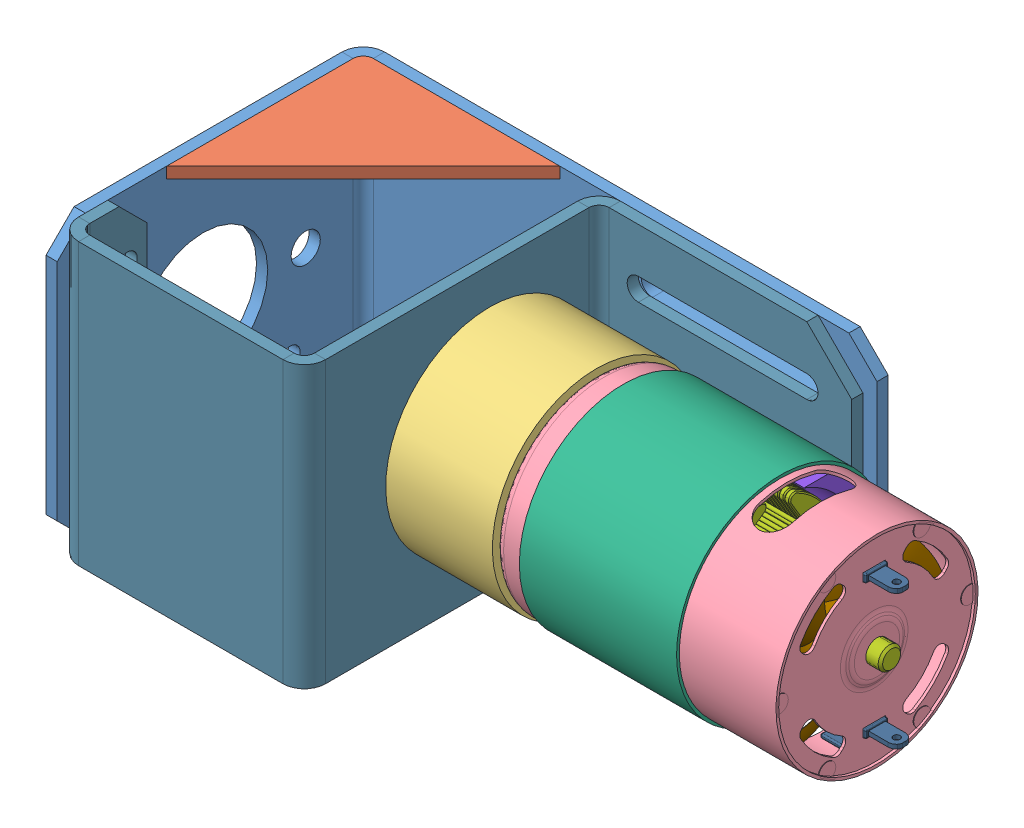
SolidWorks assembly Nema17 Holder Assem, configuration Default. Lengths in mm.
Overall size (119.88 50 56.5).
16 component instances, 14 part files, 13 mates.
Components (placement in the parent):
- Sheet Metal Nema17 LBracket-1: Sheet Metal Nema17 LBracket [Default] at (16.9581 50.3569 51.9253) size (93.5 50 56.5)
- Nema17 rib-1: Nema17 rib [Default] at (-27.7919 27.3569 53.9253) x (1 0 0) z (0 -1 0) size (35 35 2)
- Nema17 rib-2: Nema17 rib [Default] at (-27.7919 75.3569 53.9253) x (1 0 0) z (0 -1 0) size (35 35 2)
- Motor JGB37-545-1: Motor JGB37-545 [Predeterminado] at (90.0831 37.9819 73.9253) x (0 -1 0) z (-1 0 0) size (41.44 41.14 94.88)
  - Reduction box body-1: Reduction box body [Default] at (-12.375 1.5 54.875) size (37 37 25)
  - Motor body-1: Motor body [Predeterminado] at (-12.375 1.5 4.875) size (36 36 52)
  - Shaft-1: Shaft [Predeterminado] at (-12.375 8.5 67.775) x (0.863725 -0.503963 0) z (0 0 1) size (6 6 27.1)
  - Cover-1: Cover [Predeterminado] at (-12.375 1.5 22.075) size (37 36.74 28)
  - Rotor-1: Rotor [Predeterminado] at (-12.375 1.5 32.275) x (-0.951412 0.307919 0) z (0 0 1) size (26 25.6 60)
  - Magnets-1: Magnets [Default] at (-12.375 1.5 22.875) x (0 1 0) z (0 0 1) size (35 27.22 20)
  - Fan-1: Fan [Default] at (-12.375 1.5 12.975) x (-0.920955 0.389669 0) z (-0.389669 -0.920955 0) size (31.79 6.24 31.22)
  - Terminals-1: Terminals [Default] at (-12.375 1.5 5.375) x (1 0 0) z (0 0 -1) size (34 34 22.88)
  - Gear 1-1: Gear 1 [Default] at (-12.375 1.5 62.275) x (0.307919 0.951412 0) z (-0.951412 0.307919 0) size (5.97 2 5.97)
  - Gear 2-1: Gear 2 [Default] at (-12.375 -3.65 64.275) x (0.994395 0.105729 0) z (-0.105729 0.994395 0) size (20 8.6 20)
  - Gear 3-1: Gear 3 [Default] at (-12.375 8.5 66.275) x (-0.503963 -0.863725 0) z (0.863725 -0.503963 0) size (10 10 9.98)
- Part2-1: Part2 [Default] at (14.2081 50.3569 75.4253) x (0 1 0) z (1 0 0) size (50 54.5 89)
Mates (geometry in assembly coordinates):
- Coincident1: coincident anti-aligned: plane of Sheet Metal Nema17 LBracket-1 through (-27.7919 75.3569 108.4253) normal (1 0 0); plane of Nema17 rib-2 through (-27.7919 73.3569 55.7253) normal (-1 0 0)
- Coincident2: coincident anti-aligned: plane of Sheet Metal Nema17 LBracket-1 through (16.9581 50.3569 53.9253) normal (0 0 1); plane of Nema17 rib-2 through (7.2081 73.3569 53.9253) normal (0 0 -1)
- Coincident3: coincident anti-aligned: plane of Sheet Metal Nema17 LBracket-1 through (16.9581 50.3569 53.9253) normal (0 0 1); plane of Nema17 rib-1 through (7.2081 25.3569 53.9253) normal (0 0 -1)
- Coincident4: coincident anti-aligned: plane of Sheet Metal Nema17 LBracket-1 through (-27.7919 75.3569 108.4253) normal (1 0 0); plane of Nema17 rib-1 through (-27.7919 25.3569 55.7253) normal (-1 0 0)
- Coincident5: coincident aligned: plane of Sheet Metal Nema17 LBracket-1 through (-29.7919 25.3569 51.9253) normal (0 -1 0); plane of Nema17 rib-1 through (-25.9919 25.3569 55.7253) normal (0 -1 0)
- Coincident6: coincident aligned: plane of Sheet Metal Nema17 LBracket-1 through (-29.7919 75.3569 51.9253) normal (0 1 0); plane of Nema17 rib-2 through (-25.9919 75.3569 55.7253) normal (0 1 0)
- Concentric1: concentric aligned: cylinder of Sheet Metal Nema17 LBracket-1 through (-29.7919 50.3569 82.4253) axis (1 0 0) radius 11.5; cylinder of Motor JGB37-545-1/Shaft-1 through (-4.7919 50.3569 82.4253) axis (1 0 0) radius 3
- Concentric6: concentric aligned: cylinder of Motor JGB37-545-1/Shaft-1 through (-4.7919 50.3569 82.4253) axis (1 0 0) radius 3; cylinder of Part2-1 through (14.2081 50.3569 82.4253) axis (1 0 0) radius 6.5
- Coincident14: coincident aligned: plane of Sheet Metal Nema17 LBracket-1 through (-29.7919 75.3569 51.9253) normal (0 1 0); plane of Part2-1 through (16.2081 75.3569 53.9253) normal (0 1 0)
- Coincident15: coincident anti-aligned: plane of Motor JGB37-545-1/Reduction box body-1 through (16.2081 50.3569 75.4253) normal (-1 0 0); plane of Part2-1 through (16.2081 50.3569 75.4253) normal (1 0 0)
- Coincident16: coincident anti-aligned: plane of Sheet Metal Nema17 LBracket-1 through (-27.7919 75.3569 108.4253) normal (1 0 0); plane of Part2-1 through (-27.7919 50.3569 75.4253) normal (-1 0 0)
- Parallel5: parallel anti-aligned: cylinder of Part2-1 through (14.2081 58.0069 88.6755) axis (1 0 0) radius 1.75; cylinder of Motor JGB37-545-1/Reduction box body-1 through (16.2081 58.0069 88.6755) axis (-1 0 0) radius 1.7
- Concentric8: concentric anti-aligned: cylinder of Motor JGB37-545-1/Reduction box body-1 through (16.2081 42.7069 88.6755) axis (-1 0 0) radius 1.7; cylinder of Part2-1 through (14.2081 42.7069 88.6755) axis (1 0 0) radius 1.75
